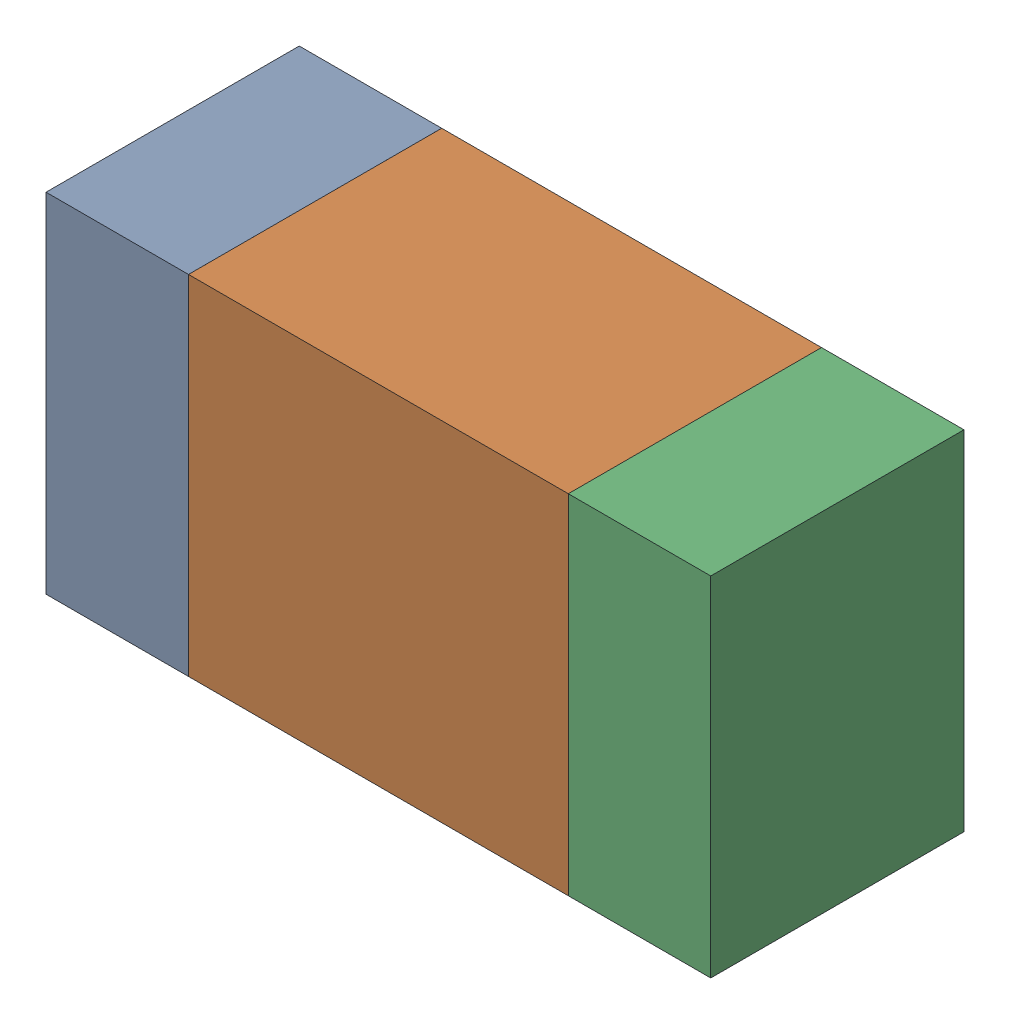
SolidWorks assembly R319_1PCB, configuration Default. Lengths in mm.
Overall size (1.05 0.55 0.4).
6 component instances, 2 part files, 0 mates.
Components (placement in the parent):
- 854785432-1: 854785432 [Default] at (135.1876 109.8001 -2.0638) size (0.22 0.55 0.4)
  - Extruded-1: Extruded [Default] at origin size (0.22 0.55 0.4)
- 854785568-1: 854785568 [Default] at (135.6001 109.8001 -2.0638) size (0.6 0.55 0.4)
  - Extruded_2-1: Extruded_2 [Default] at origin size (0.6 0.55 0.4)
- 854785432-2: 854785432 [Default] at (136.0126 109.8001 -2.0638) size (0.22 0.55 0.4)
  - Extruded-1: Extruded [Default] at origin size (0.22 0.55 0.4)
